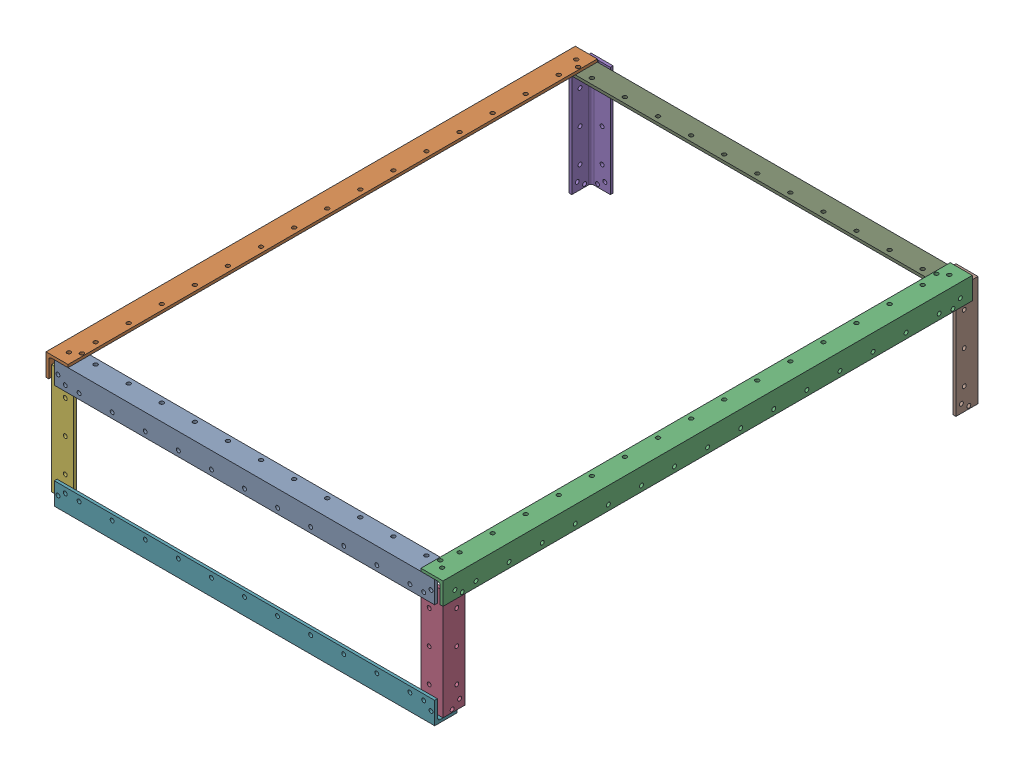
SolidWorks assembly L-Bar Frame, configuration Default. Lengths in mm.
Overall size (457.2 149.22 624.56).
9 component instances, 3 part files, 0 mates.
Components (placement in the parent):
- L-Bar_1x1_8th_inch_558.8mm-1: L-Bar_1x1_8th_inch_558.8mm [Default] at (31.763 133.5629 397.0773) x (0 0 -1) z (-1 0 0) size (25.4 25.4 438.15)
- L-Bar_1x1_8th_inch-1: L-Bar_1x1_8th_inch [Default] at (-196.837 136.7379 92.2773) x (1 0 0) z (0 0 -1) size (25.4 25.4 609.6)
- L-Bar_1x1_8th_inch-2: L-Bar_1x1_8th_inch [Default] at (260.363 136.7379 92.2773) x (-1 0 0) z (0 0 1) size (25.4 25.4 609.6)
- L-Bar_1x1_8th_4inch-1: L-Bar_1x1_8th_4inch [Default] at (257.188 60.5379 393.9023) x (-1 0 0) z (0 -1 0) size (25.4 25.4 127)
- L-Bar_1x1_8th_4inch-2: L-Bar_1x1_8th_4inch [Default] at (-193.662 60.5379 -227.4871) x (1 0 0) z (0 -1 0) size (25.4 25.4 127)
- L-Bar_1x1_8th_4inch-3: L-Bar_1x1_8th_4inch [Default] at (-193.662 60.5379 393.9023) x (1 0 0) z (0 1 0) size (25.4 25.4 127)
- L-Bar_1x1_8th_inch_558.8mm-2: L-Bar_1x1_8th_inch_558.8mm [Default] at (31.763 -12.4871 397.0773) x (0 0 -1) z (1 0 0) size (25.4 25.4 438.15)
- L-Bar_1x1_8th_4inch-4: L-Bar_1x1_8th_4inch [Default] at (251.9928 60.5379 -227.4871) x (-1 0 0) z (0 1 0) size (25.4 25.4 127)
- L-Bar_1x1_8th_inch_558.8mm-3: L-Bar_1x1_8th_inch_558.8mm [Default] at (31.763 133.5629 -212.5227) x (0 -1 0) z (-1 0 0) size (25.4 25.4 438.15)
